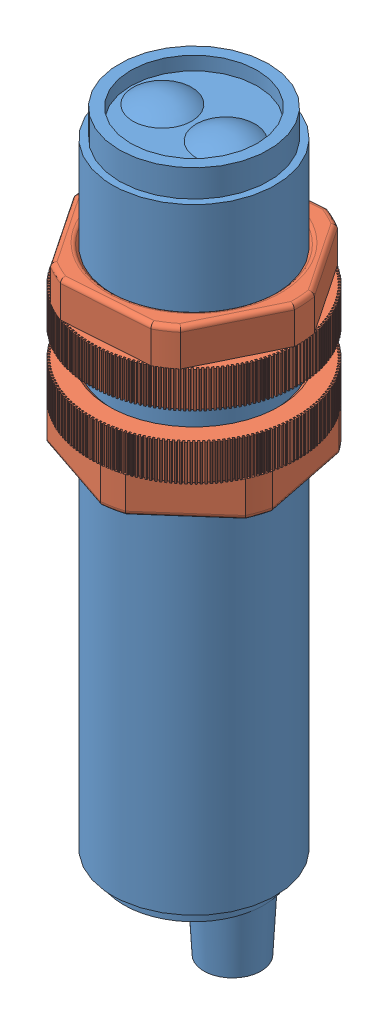
SolidWorks assembly photoelectric sensor, configuration Default. Lengths in mm.
Overall size (31.92 79 31.92).
3 component instances, 2 part files, 3 mates.
Components (placement in the parent):
- sensor photo elektrik-1: sensor photo elektrik [Default] at origin size (18 79 18)
- sensor clamp-1: sensor clamp [Default] at (0 39.0167 0) x (0.980349 0 -0.197271) z (0.197271 0 0.980349) size (23 8.03 23)
- sensor clamp-2: sensor clamp [Default] at (0 58.0167 0) x (-0.830005 0 0.557755) z (0.557755 0 0.830005) size (23 8.03 23)
Mates (geometry in assembly coordinates):
- Concentric1: concentric aligned: cylinder of sensor photo elektrik-1 through (0 71 0) axis (0 -1 0) radius 8.25; cylinder of sensor clamp-1 through (0 43.0167 0) axis (0 -1 0) radius 8.9
- Distance1: distance = 3 mm anti-aligned: plane of sensor clamp-2 through (0 50.0167 0) normal (0 -1 0); plane of sensor clamp-1 through (0 47.0167 0) normal (0 1 0)
- Concentric2: concentric aligned: circle of sensor photo elektrik-1; cylinder of sensor clamp-2 through (0 54.0167 0) axis (0 1 0) radius 8.9
